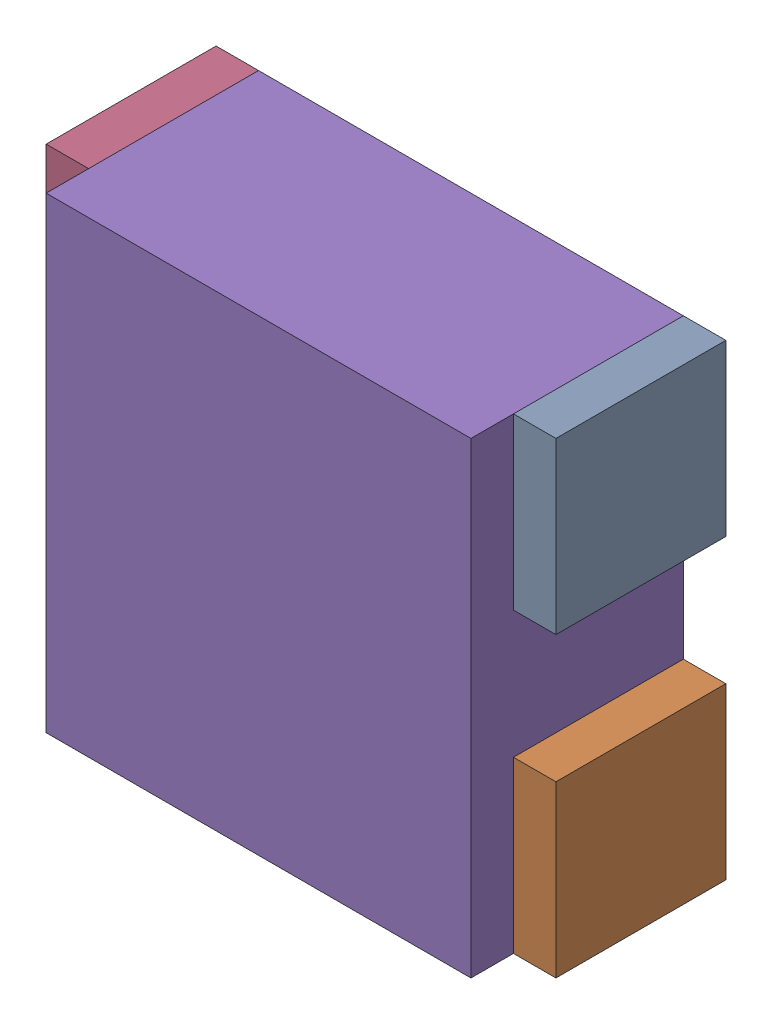
SolidWorks assembly RN19, configuration Default. Lengths in mm.
Overall size (1.2 1.1 0.5).
10 component instances, 2 part files, 0 mates.
Components (placement in the parent):
- 791587232-1: 791587232 [Default] at (119 73.15 0) size (0.1 0.4 0.4)
  - Extruded_10-1: Extruded_10 [Default] at origin size (0.1 0.4 0.4)
- 791587232-2: 791587232 [Default] at (119 72.45 0) size (0.1 0.4 0.4)
  - Extruded_10-1: Extruded_10 [Default] at origin size (0.1 0.4 0.4)
- 791587232-3: 791587232 [Default] at (117.9 72.45 0) size (0.1 0.4 0.4)
  - Extruded_10-1: Extruded_10 [Default] at origin size (0.1 0.4 0.4)
- 791587232-4: 791587232 [Default] at (117.9 73.15 0) size (0.1 0.4 0.4)
  - Extruded_10-1: Extruded_10 [Default] at origin size (0.1 0.4 0.4)
- 836749552-1: 836749552 [Default] at (118.45 72.8 0) size (1 1.1 0.5)
  - Extruded_11-1: Extruded_11 [Default] at origin size (1 1.1 0.5)
